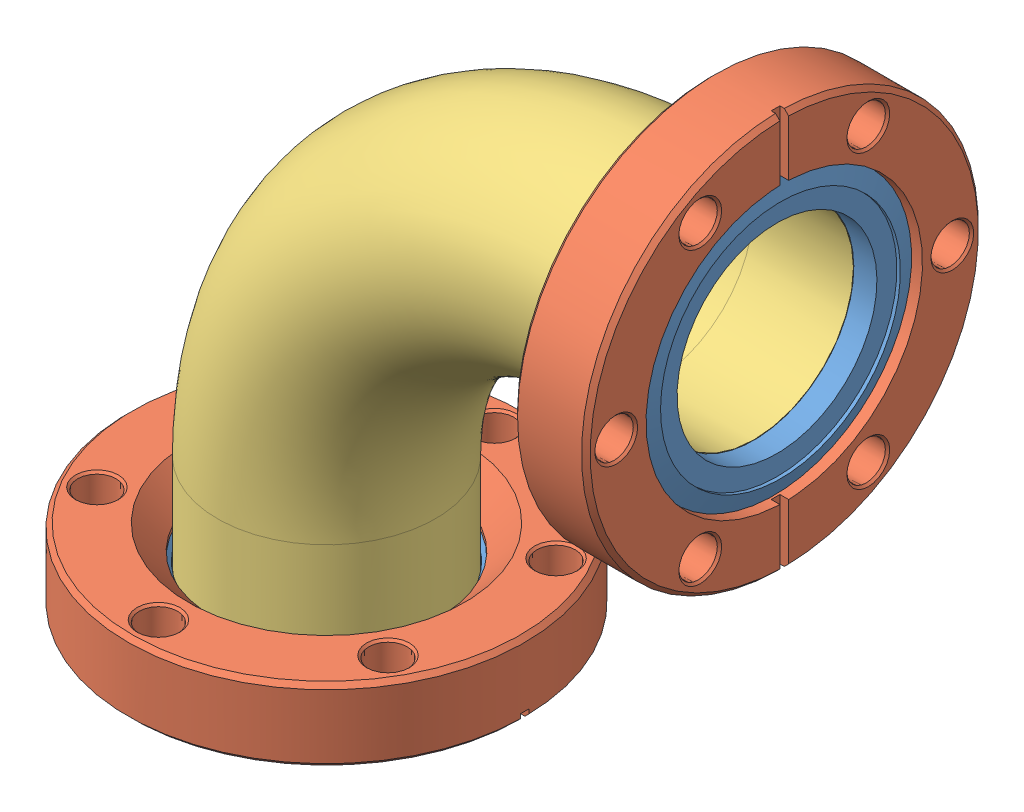
SolidWorks assembly 403042, configuration Default. Lengths in mm.
Overall size (127.35 127.35 94.72).
5 component instances, 3 part files, 0 mates.
Components (placement in the parent):
- 910014 (2.75 ROTA INSERT)-1: 910014 (2.75 ROTA INSERT) [Default] at (0 2.3114 0) x (-0.343989 0 0.938974) z (0 -1 0) size (48.06 48.06 6.96)
- 915002 (2.75 ROTA FLANGE)-1: 915002 (2.75 ROTA FLANGE) [Default] at (79.9846 74.676 0) x (0 0.5 -0.866025) z (1 0 0) size (69.34 69.34 12.7)
- 915002 (2.75 ROTA FLANGE)-2: 915002 (2.75 ROTA FLANGE) [Default] at (0 -5.3086 0) x (0.5 0 -0.866025) z (0 -1 0) size (69.34 69.34 12.7)
- 042207-1: 042207 [Default] at origin size (93.73 93.73 38.1)
- 910014 (2.75 ROTA INSERT)-2: 910014 (2.75 ROTA INSERT) [Default] at (72.3646 74.676 0) x (0 0.872746 -0.488175) z (1 0 0) size (48.06 48.06 6.96)
